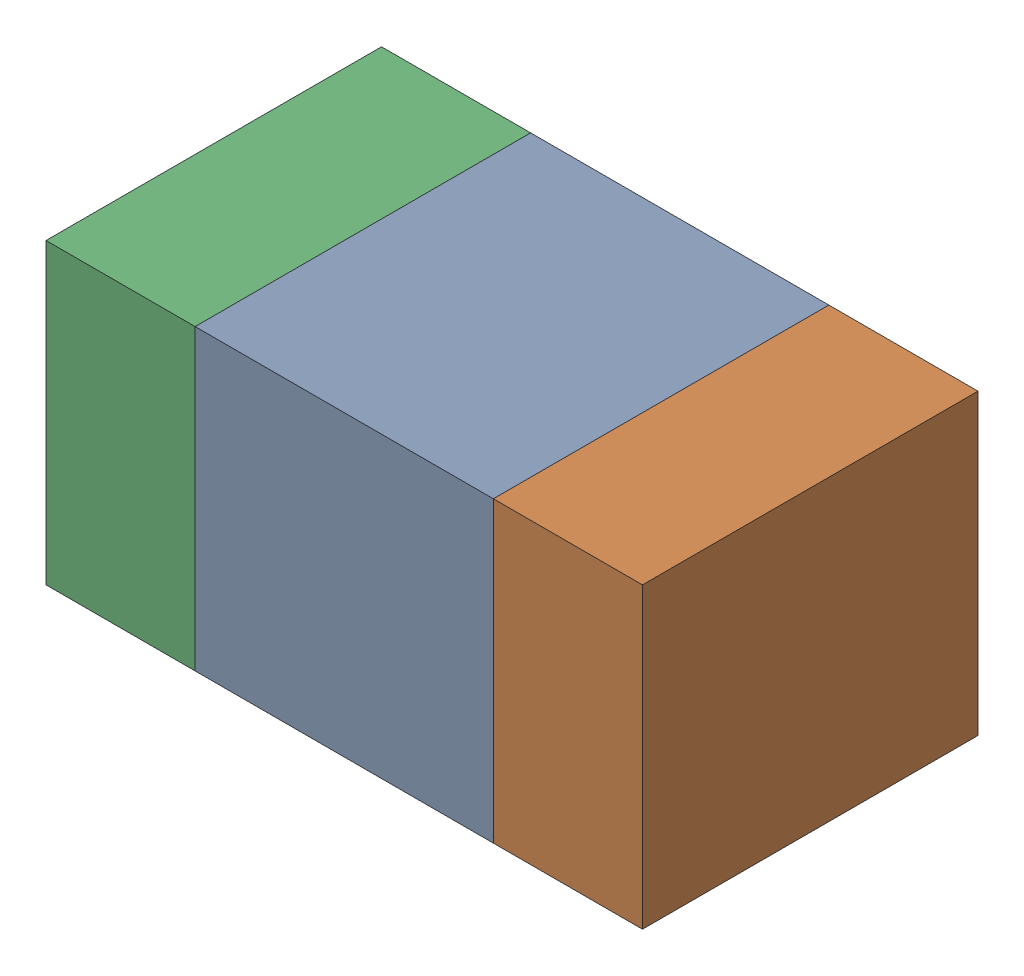
SolidWorks assembly C7, configuration ﾃﾞﾌｫﾙﾄ. Lengths in mm.
Overall size (1.6 0.8 0.9).
6 component instances, 2 part files, 0 mates.
Components (placement in the parent):
- 689259608-1: 689259608 [ﾃﾞﾌｫﾙﾄ] at (72.5 50.7501 0) size (0.8 0.8 0.9)
  - Extruded_3-1: Extruded_3 [ﾃﾞﾌｫﾙﾄ] at origin size (0.8 0.8 0.9)
- 689259744-1: 689259744 [ﾃﾞﾌｫﾙﾄ] at (73.1001 50.7501 0) size (0.4 0.8 0.9)
  - Extruded_4-1: Extruded_4 [ﾃﾞﾌｫﾙﾄ] at origin size (0.4 0.8 0.9)
- 689259744-2: 689259744 [ﾃﾞﾌｫﾙﾄ] at (71.9001 50.7501 0) size (0.4 0.8 0.9)
  - Extruded_4-1: Extruded_4 [ﾃﾞﾌｫﾙﾄ] at origin size (0.4 0.8 0.9)
